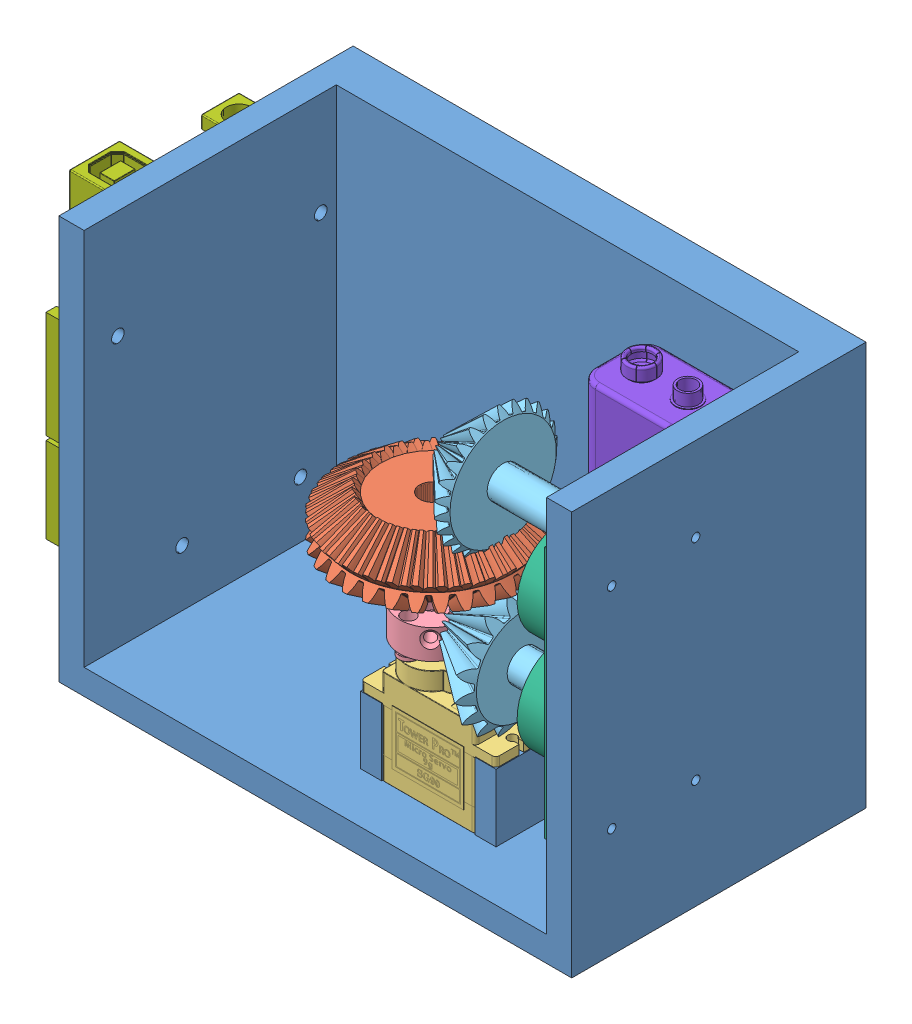
SolidWorks assembly BUG, configuration Default. Lengths in mm.
Overall size (134.5 112.93 144.75).
14 component instances, 10 part files, 24 mates.
Components (placement in the parent):
- Body-1: Body [Default] at (33.0559 68.7048 61.8097) size (122 112.32 144.75)
- straight bevel gear_am-2: straight bevel gear_am [Metric - Straight bevel gear 1.375M 30GT 26PT 20PA 10FW ---30OH0MD6N] at (42.6559 75.8291 113.5755) x (0 1 0) z (0.140177 0 0.990126) size (9.35 42.81 42.94)
- straight bevel gear_am-5: straight bevel gear_am [Metric - Straight bevel gear 1.375M 30GT 23PT 20PA 10FW ---30OH0MD6N] at (42.6559 75.8289 113.5755) x (0 -1 0) z (-0.019594 0 -0.999808) size (9 42.58 42.7)
- Part2^BUG-1: Part2^BUG [Default] at origin (virtual)
- SG90 - Micro Servo 9g - Tower Pro.1-1: SG90 - Micro Servo 9g - Tower Pro.1 [Peça] at (47.8059 34.2548 113.5755) size (32.1 29.95 13.39)
- Micro sized Servo Mount - x4-1: Micro sized Servo Mount - x4 [Quatro] at (42.6559 53.5548 113.5755) x (0.999625 0 -0.027372) z (0 -1 0) size (16.2 16.2 10.2)
- new2 (1)-1: new2 (1) [Default] at (35.9964 59.6301 103.5188) x (-1 0 0) z (0 -0.652197 0.758049) size (44.09 28.46 28.46)
  - straight bevel pinion_ai-1: straight bevel pinion_ai [Inch - Straight bevel pinion 16DP16PT 26GT 20PA 10FW ---16O0.3H1.9MD0.25N] at (-28.2686 -5.4266 8.5977) size (44.09 28.46 28.46)
- straight bevel gear_am-4: straight bevel gear_am [Metric - Straight bevel gear 1.375M 30GT 23PT 20PA 10FW ---30OH0MD6N] at (42.6559 75.8291 113.5755) x (0 1 0) z (0.992227 0 -0.124443) size (9 42.58 42.7)
- straight bevel pinion_ai-2: straight bevel pinion_ai [Inch - Straight bevel pinion 24DP26PT 30GT 20PA 10FW ---26O0.3H1.9MD0.25N] at (59.5026 93.5216 113.5755) x (-1 0 0) z (0 0.531747 -0.846903) size (45.21 29.23 29.39)
- for bearings-1: for bearings [Default] at (88.0559 68.7048 112.3097) x (0 1 0) z (-1 0 0) size (82.87 40.99 15)
- Part1^BUG-1: Part1^BUG [Default] at origin (virtual)
- arduinoUno-1: arduinoUno [Detailed] at (-27.9441 70.1948 99.6697) x (0 -1 0) z (0 0 -1) size (75.4 14.5 53.4)
- 9V-2-1: 9V-2 [Default] at (64.2034 52.7302 79.8097) size (25 49.55 16)
Mates (geometry in assembly coordinates):
- Coincident1: coincident: plane of straight bevel gear_am-2 through (42.6559 75.829 113.5755) normal (0 -1 0); plane of straight bevel gear_am-5 through (42.6559 75.829 113.5755) normal (0 1 0)
- Coincident2: coincident: circle of straight bevel gear_am-2; circle of straight bevel gear_am-5
- Parallel1: parallel: plane of Body-1 through (88.0559 23.7048 131.8097) normal (0 1 0); plane of straight bevel gear_am-5 through (42.6559 69.0211 113.5755) normal (0 -1 0)
- Coincident5: coincident: plane of Body-1 through (88.0559 23.7048 131.8097) normal (0 1 0); plane of SG90 - Micro Servo 9g - Tower Pro.1-1 through (37.4059 23.7048 118.8255) normal (0 -1 0)
- Coincident6: coincident: plane of Body-1 through (59.0559 39.7048 119.8097) normal (-1 0 0); plane of SG90 - Micro Servo 9g - Tower Pro.1-1 through (59.0559 39.4048 118.8255) normal (1 0 0)
- Parallel2: parallel: plane of Body-1 through (36.8559 39.7048 119.8097) normal (1 0 0); plane of SG90 - Micro Servo 9g - Tower Pro.1-1 through (36.5559 39.4048 118.8255) normal (-1 0 0)
- Concentric1: concentric: circle of straight bevel gear_am-2; circle of SG90 - Micro Servo 9g - Tower Pro.1-1
- Concentric3: concentric: circle of SG90 - Micro Servo 9g - Tower Pro.1-1; circle of Micro sized Servo Mount - x4-1
- Coincident9: coincident: plane of SG90 - Micro Servo 9g - Tower Pro.1-1 through (42.6559 50.4548 113.5755) normal (0 1 0); circle of Micro sized Servo Mount - x4-1
- Coincident11: coincident: plane of straight bevel gear_am-5 through (42.6559 75.829 113.5755) normal (0 1 0); plane of straight bevel gear_am-4 through (42.6559 75.829 113.5755) normal (0 -1 0)
- Concentric5: concentric: circle of straight bevel gear_am-5; circle of straight bevel gear_am-4
- Parallel3: parallel: plane of Body-1 through (94.0559 17.7048 131.8097) normal (1 0 0); plane of straight bevel pinion_ai-2 through (59.5026 93.5216 113.5755) normal (1 0 0)
- Coincident17: coincident: point of straight bevel gear_am-4; point of straight bevel pinion_ai-2
- Parallel6: parallel: plane of Body-1 through (94.0559 17.7048 131.8097) normal (1 0 0); plane of new2 (1)-1/straight bevel pinion_ai-1 through (64.265 58.1363 113.5755) normal (1 0 0)
- Coincident21: coincident: point of straight bevel gear_am-5; point of new2 (1)-1/straight bevel pinion_ai-1
- Concentric7: concentric: circle of Micro sized Servo Mount - x4-1; circle of straight bevel gear_am-4
- Coincident22: coincident: plane of Body-1 through (-27.9441 17.7048 131.8097) normal (-1 0 0); plane of arduinoUno-1 through (-27.9441 70.1948 99.6697) normal (1 0 0)
- Concentric8: concentric: circle of Body-1; circle of arduinoUno-1
- Coincident29: coincident: plane of Body-1 through (88.0559 23.7048 131.8097) normal (-1 0 0); plane of for bearings-1 through (88.0559 68.7048 112.3097) normal (1 0 0)
- Parallel11: parallel: plane of Body-1 through (33.0559 68.7048 131.8097) normal (0 0 1); plane of for bearings-1 through (83.0559 98.7048 127.3097) normal (0 0 1)
- Concentric17: concentric: circle of Body-1; circle of for bearings-1
- Lock1: lock: unknown of Body-1; unknown of SG90 - Micro Servo 9g - Tower Pro.1-1
- Lock2: lock: unknown of straight bevel gear_am-5; unknown of straight bevel gear_am-4
- Coincident30: coincident: plane of Body-1 through (-27.9441 119.7048 71.8097) normal (0 0 1); plane of 9V-2-1 through (51.7034 98.7302 71.8097) normal (0 0 -1)
